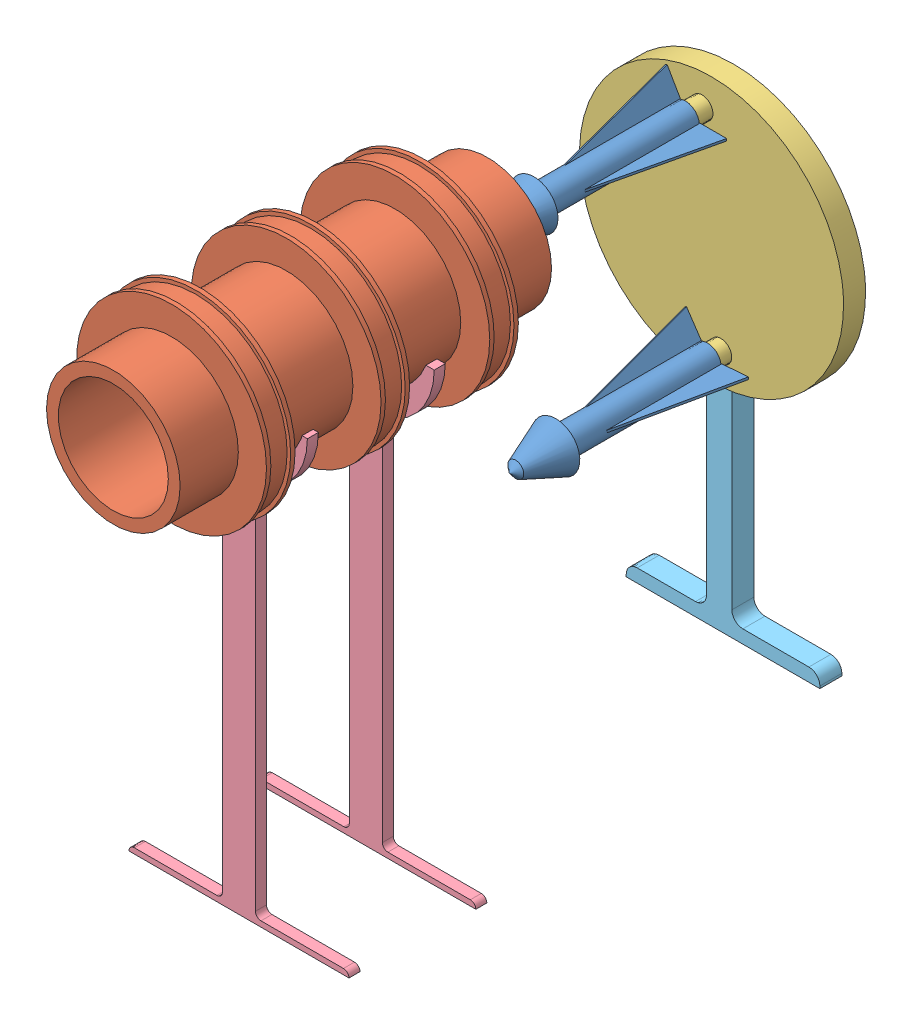
SolidWorks assembly Assembly_torpedo-system1, configuration Default. Lengths in mm.
Overall size (130.63 256.64 287.04).
7 component instances, 5 part files, 3 mates.
Components (placement in the parent):
- torpedo-1: torpedo [Default] at (-3.8488 -17.569 24.0131) size (29.19 32.22 90.35)
- barrel-1: barrel [Default] at (-3.8488 -17.569 142.1776) size (86.29 86.29 170)
- gattling disk-2: gattling disk [Default] at (0.4248 -63.3549 -50.3437) x (0.995672 0.092935 0) z (0 0 1) size (120 120 30)
- torpedo-2: torpedo [Default] at (4.6984 -109.1408 22.6452) x (0.997465 0.071153 0) z (0 0 1) size (29.19 32.22 90.35)
- barrel_stand-1: barrel_stand [Default] at (-3.8027 -27.1391 167.6477) size (100 202.74 5)
- barrel_stand-2: barrel_stand [Default] at (-3.1956 -28.3221 110.6129) size (100 202.74 5)
- gattling_stand-1: gattling_stand [Default] at (-5.337 -62.5724 -59.8607) size (88 173.98 10)
Mates (geometry in assembly coordinates):
- Concentric2: concentric aligned: cylinder of torpedo-1 through (-3.8488 -17.569 68.6917) axis (0 0 1) radius 6.2668; cylinder of barrel-1 through (-3.8488 -17.569 261.2383) axis (0 0 1) radius 25
- Concentric3: concentric anti-aligned: cylinder of torpedo-1 through (-3.8488 -17.569 68.6917) axis (0 0 1) radius 4.933; cylinder of gattling disk-2 through (-3.8488 -17.569 -20.3437) axis (0 0 -1) radius 4.92
- Concentric4: concentric anti-aligned: cylinder of gattling disk-2 through (4.6984 -109.1408 -20.3437) axis (0 0 -1) radius 4.92; cylinder of torpedo-2 through (4.6984 -109.1408 67.3237) axis (0 0 1) radius 4.933
